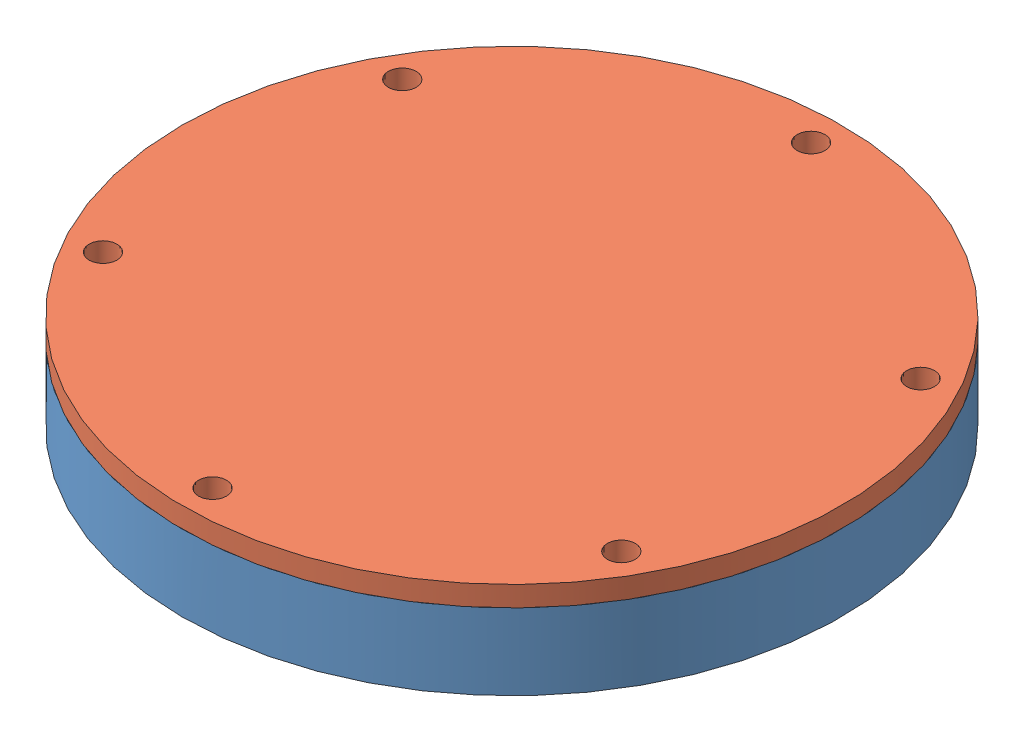
SolidWorks assembly EnsamblajeCamaraSecadoVacio, configuration Predeterminado. Lengths in mm.
Overall size (130 36.53 130).
3 component instances, 3 part files, 5 mates.
Components (placement in the parent):
- CamaraSecadoVacio-1: CamaraSecadoVacio [Predeterminado] at (0.6484 30.3152 130) size (130 15 130)
- TapaCamaraSecadoVacio-1: TapaCamaraSecadoVacio [Predeterminado] at (0.6484 34.3152 130) size (130 6 130)
- Hose Barb to Male Pipe 125HB-2-2-1: Hose Barb to Male Pipe 125HB-2-2 [Predeterminado] at (0.6484 -2.2108 130) x (0 1 0) z (0 0 1) size (27.18 11.11 12.83)
Mates (geometry in assembly coordinates):
- Coincidente3: coincident: plane of assembly; plane of assembly; plane of CamaraSecadoVacio-1 through (0.6484 30.3152 130) normal (0 1 0); plane of TapaCamaraSecadoVacio-1 through (-64.3516 30.3152 130) normal (0 -1 0)
- Concéntrica1: concentric: cylinder of assembly; cylinder of assembly; cylinder of CamaraSecadoVacio-1 through (0.6484 15.3152 130) axis (0 1 0) radius 65; cylinder of TapaCamaraSecadoVacio-1 through (0.6484 93.8133 130) axis (0 1 0) radius 65
- Concéntrica2: concentric: circle of assembly; circle of assembly; circle of CamaraSecadoVacio-1; circle of TapaCamaraSecadoVacio-1
- Concéntrica3: concentric: cylinder of assembly; cylinder of assembly; cylinder of CamaraSecadoVacio-1 through (0.6484 15.3152 130) axis (0 -1 0) radius 4.4; cylinder of Hose Barb to Male Pipe 125HB-2-2-1 through (0.6484 15.3152 130) axis (0 1 0) radius 5.2146
- Coincidente4: coincident: plane of assembly; plane of assembly; plane of CamaraSecadoVacio-1 through (0.6484 15.3152 130) normal (0 -1 0); plane of Hose Barb to Male Pipe 125HB-2-2-1 through (0.6484 15.3152 130) normal (0 1 0)
